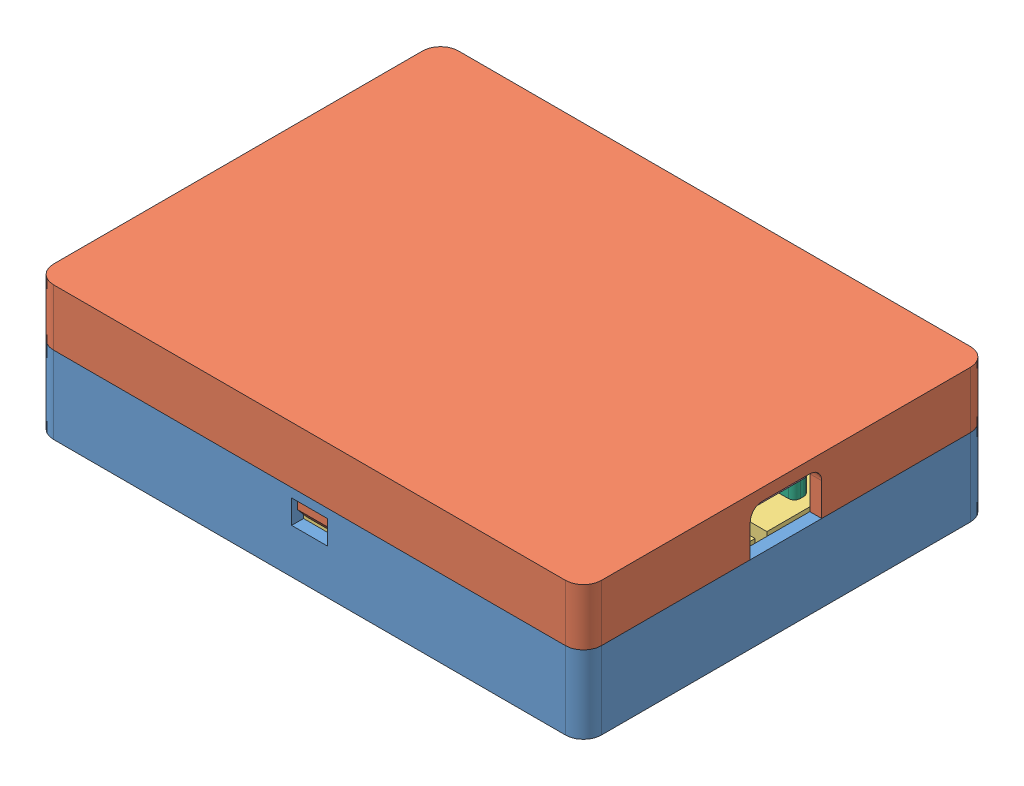
SolidWorks assembly enclosure_layout, configuration Default. Lengths in mm.
Overall size (92 22.5 68).
10 component instances, 7 part files, 3 mates.
Components (placement in the parent):
- red_bear_enclosure_assy-1: red_bear_enclosure_assy [Default] at origin size (92 22.5 68)
  - case_base-1: case_base [Default] at origin size (92 13 68)
  - case_lid-1: case_lid [Default] at (0 22.5 0) x (1 0 0) z (0 0 -1) size (92 14.5 68)
- redbear_breadboard_assy-1: redbear_breadboard_assy [Default] at (41.8 2.5 -27.3) size (84.7 15.5 56.7)
  - Breadboard2-1: Breadboard2 [Default] at origin size (84.7 9 56.7)
  - redbear_duo_assy-1: redbear_duo_assy [Default] at (-40.8953 9.736 46.697) x (0 0 -1) z (1 0 0) size (20.4 6.5 39)
    - Component1-1: Component1 [Default] at (19.197 -0.736 15.8953) size (20.4 1.2 38)
    - Component2-1: Component2 [Default] at (19.197 3.264 15.8953) size (2.6 2.6 30.8)
    - Component3-1: Component3 [Default] at (19.197 -0.736 15.8953) size (2.6 2.6 30.8)
    - Component4-1: Component4 [Default] at (19.197 -0.736 15.1953) size (7.8 2.7 6)
Mates (geometry in assembly coordinates):
- Distance4: distance = 0.5 mm anti-aligned: plane of red_bear_enclosure_assy-1/case_base-1 through (0 2 0) normal (0 1 0); plane of redbear_breadboard_assy-1/Breadboard2-1 through (42.8 2.5 0) normal (0 -1 0)
- Distance1: distance = 2.2 mm anti-aligned: plane of redbear_breadboard_assy-1/Breadboard2-1 through (41.8 8.5 -27.3) normal (1 0 0); plane of red_bear_enclosure_assy-1/case_base-1 through (44 13 -34) normal (-1 0 0)
- Distance3: distance = 4.7 mm anti-aligned: plane of red_bear_enclosure_assy-1/case_base-1 through (-46 13 -32) normal (0 0 1); plane of redbear_breadboard_assy-1/Breadboard2-1 through (-40.8 8.5 -27.3) normal (0 0 -1)
